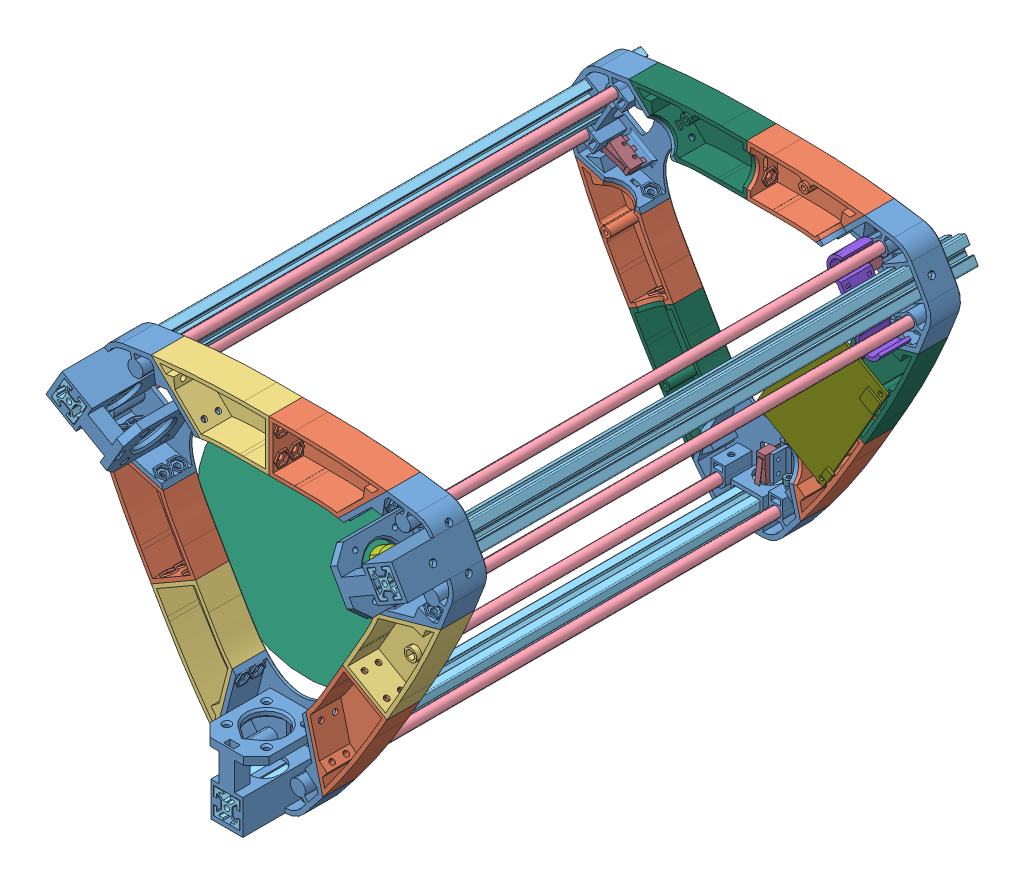
SolidWorks assembly 3DR Simple Delta Printer, configuration Default. Lengths in mm.
Overall size (377.93 326.93 450).
77 component instances, 20 part files, 59 mates.
Components (placement in the parent):
- Bottom Triangle Assembly-1: Bottom Triangle Assembly [Default] at origin size (216 130.25 60.11)
  - 3DR Bottom Motor Mount-1: 3DR Bottom Motor Mount [Simple Center] at origin size (84 76.99 60.11)
  - Wings-1: Wings [Longer with Nut] at (42.1437 10.9951 0) x (0.968477 0.249105 0) z (0 0 1) size (67.81 90.53 27.11)
  - MirrorWings-2: MirrorWings [Default] at (-42.1437 10.9951 0) x (-0.968477 0.249105 0) z (0 0 -1) (suppressed, hidden)
  - MirrorWings1-2: MirrorWings1 [Top With Dimples] at (-42.1437 10.9951 0) x (-0.968477 0.249105 0) z (0 0 -1) (suppressed, hidden)
  - Microswitch-1: Microswitch [Default] at (12 33.25 15) x (0 1 0) z (1 0 0) (suppressed, hidden)
  - Cap Head Screw-1: Cap Head Screw [M4 x 10] at (22.5 12.7724 13.5) x (0.845486 0 0.533998) z (0 1 0) (suppressed, hidden)
  - Wing Mirror Long-1: Wing Mirror Long [Longer With Dimple] at (-134.6068 171.146 0) x (-0.268507 -0.963278 0) z (0 0 1) size (89.72 68.95 27.11)
  - Wing Mirror Long Top-1: Wing Mirror Long Top [Longer Top With Dimples] at (-134.6068 171.146 0) x (-0.268507 -0.963278 0) z (0 0 1) (suppressed, hidden)
- Bottom Triangle Assembly-2: Bottom Triangle Assembly [Default] at (-123.057 213.141 0) x (-0.5 -0.866025 0) z (0 0 1) size (216 130.25 60.11)
  - 3DR Bottom Motor Mount-1: 3DR Bottom Motor Mount [Simple Center] at origin size (84 76.99 60.11)
  - Wings-1: Wings [Longer with Nut] at (42.1437 10.9951 0) x (0.968477 0.249105 0) z (0 0 1) size (67.81 90.53 27.11)
  - MirrorWings-2: MirrorWings [Default] at (-42.1437 10.9951 0) x (-0.968477 0.249105 0) z (0 0 -1) (suppressed, hidden)
  - MirrorWings1-2: MirrorWings1 [Top With Dimples] at (-42.1437 10.9951 0) x (-0.968477 0.249105 0) z (0 0 -1) (suppressed, hidden)
  - Microswitch-1: Microswitch [Default] at (12 33.25 15) x (0 1 0) z (1 0 0) (suppressed, hidden)
  - Cap Head Screw-1: Cap Head Screw [M4 x 10] at (22.5 12.7724 13.5) x (0.845486 0 0.533998) z (0 1 0) (suppressed, hidden)
  - Wing Mirror Long-1: Wing Mirror Long [Longer With Dimple] at (-134.6068 171.146 0) x (-0.268507 -0.963278 0) z (0 0 1) size (89.72 68.95 27.11)
  - Wing Mirror Long Top-1: Wing Mirror Long Top [Longer Top With Dimples] at (-134.6068 171.146 0) x (-0.268507 -0.963278 0) z (0 0 1) (suppressed, hidden)
- Bottom Triangle Assembly-3: Bottom Triangle Assembly [Default] at (123.057 213.141 0) x (-0.5 0.866025 0) z (0 0 1) size (216 130.25 60.11)
  - 3DR Bottom Motor Mount-1: 3DR Bottom Motor Mount [Simple Center] at origin size (84 76.99 60.11)
  - Wings-1: Wings [Longer with Nut] at (42.1437 10.9951 0) x (0.968477 0.249105 0) z (0 0 1) size (67.81 90.53 27.11)
  - MirrorWings-2: MirrorWings [Default] at (-42.1437 10.9951 0) x (-0.968477 0.249105 0) z (0 0 -1) (suppressed, hidden)
  - MirrorWings1-2: MirrorWings1 [Top With Dimples] at (-42.1437 10.9951 0) x (-0.968477 0.249105 0) z (0 0 -1) (suppressed, hidden)
  - Microswitch-1: Microswitch [Default] at (12 33.25 15) x (0 1 0) z (1 0 0) (suppressed, hidden)
  - Cap Head Screw-1: Cap Head Screw [M4 x 10] at (22.5 12.7724 13.5) x (0.845486 0 0.533998) z (0 1 0) (suppressed, hidden)
  - Wing Mirror Long-1: Wing Mirror Long [Longer With Dimple] at (-134.6068 171.146 0) x (-0.268507 -0.963278 0) z (0 0 1) size (89.72 68.95 27.11)
  - Wing Mirror Long Top-1: Wing Mirror Long Top [Longer Top With Dimples] at (-134.6068 171.146 0) x (-0.268507 -0.963278 0) z (0 0 1) (suppressed, hidden)
- RGOCG8-400-1: RGOCG8-400 [Default] at (126.9025 189.3804 -377) size (8 8 400)
- HFSB5-2020-450-1: HFSB5-2020-450 [Default] at (123.2735 213.266 60) x (0.866025 0.5 0) z (0 0 1) size (20 20 450)
- Round Plate-1: Round Plate [Default] at (0 142.094 -5) x (0.976638 0.214891 0) z (0 0 1) size (170 170 3)
- RGOCG8-400-2: RGOCG8-400 [Default] at (104.4025 228.3516 -377) size (8 8 400)
- RGOCG8-400-3: RGOCG8-400 [Default] at (22.5 8.55 -377) size (8 8 400)
- RGOCG8-400-4: RGOCG8-400 [Default] at (-22.5 8.55 -377) size (8 8 400)
- RGOCG8-400-5: RGOCG8-400 [Default] at (-126.9025 189.3804 -377) size (8 8 400)
- RGOCG8-400-6: RGOCG8-400 [Default] at (-104.4025 228.3516 -377) size (8 8 400)
- HFSB5-2020-450-2: HFSB5-2020-450 [Default] at (-123.2735 213.266 60) x (0.5 0.866025 0) z (0 0 1) size (20 20 450)
- HFSB5-2020-450-3: HFSB5-2020-450 [Default] at (0 -0.25 60) size (20 20 450)
- Spiral Bed Clamp-1: Spiral Bed Clamp [Default] at (110.1044 146.1492 -5.917) x (0.34446 -0.938801 0) z (0 0 1) size (25.27 21.2 7.51) (hidden)
- Spool-1: Spool [Default] at (113.3142 207.516 29) x (0.25 -0.433013 0.866025) z (-0.866025 -0.5 0) size (21.5 23.26 25)
- Carriage for LM8UU-1: Carriage for LM8UU [Default] at (113.1669 207.431 -338.0967) x (-0.5 0.866025 0) z (0 0 1) size (65 26.86 24)
- Spectra Idler-1: Spectra Idler [Default] at (109.6336 205.391 -375.1359) x (0 0 1) z (-0.866025 -0.5 0) size (15.69 15.69 24.76)
  - 624ZZ-1: 624ZZ [Default] at origin size (13 13 5)
  - 624ZZ-2: 624ZZ [Default] at (0 0 5) size (13 13 5)
  - Nut-1: Nut [M5] at (0 0 -4.75) size (9.12 7.9 3.75)
  - Washer-1: Washer [M5] at (0 0 10) size (9.75 9.75 1)
  - Washer-2: Washer [M5] at (0 0 -1) size (9.75 9.75 1)
  - Washer-3: Washer [M5 Fender] at (0 0 -5.75) x (0.384822 -0.922991 0) z (0 0 1) size (12 12 1)
  - Button Head Screw-1: Button Head Screw [M5 x 22] at (0 0 -11) size (9.5 9.5 24.76)
- Bottom Triangle Assembly-4: Bottom Triangle Assembly [Top] at (123.057 213.141 -370) x (-0.5 0.866025 0) z (0 0 1) size (216 130.25 28.11)
  - 3DR Bottom Motor Mount-1: 3DR Bottom Motor Mount [Top Microswitch Small] at origin size (84 76.99 24.11)
  - Wings-1: Wings [Longer Top Nuts] at (42.1437 10.9951 0) x (0.968477 0.249105 0) z (0 0 1) size (67.81 90.53 26.11)
  - MirrorWings-2: MirrorWings [Default] at (-42.1437 10.9951 0) x (-0.968477 0.249105 0) z (0 0 -1) (suppressed, hidden)
  - MirrorWings1-2: MirrorWings1 [Top With Dimples] at (-42.1437 10.9951 0) x (-0.968477 0.249105 0) z (0 0 -1) (suppressed, hidden)
  - Microswitch-1: Microswitch [Default] at (12 33.25 15) x (0 1 0) z (1 0 0)
  - Cap Head Screw-1: Cap Head Screw [M4 x 10] at (22.5 12.7724 13.5) x (0.845486 0 0.533998) z (0 1 0)
  - Wing Mirror Long-1: Wing Mirror Long [Longer With Dimple] at (-134.6068 171.146 0) x (-0.268507 -0.963278 0) z (0 0 1) size (89.72 68.95 27.11) (suppressed, hidden)
  - Wing Mirror Long Top-1: Wing Mirror Long Top [Longer Top With Dimples] at (-134.6068 171.146 0) x (-0.268507 -0.963278 0) z (0 0 1)
- Bottom Triangle Assembly-6: Bottom Triangle Assembly [Top] at (-123.057 213.141 -370) x (-0.5 -0.866025 0) z (0 0 1) size (216 130.25 28.11)
  - 3DR Bottom Motor Mount-1: 3DR Bottom Motor Mount [Top Microswitch Small] at origin size (84 76.99 24.11)
  - Wings-1: Wings [Longer Top Nuts] at (42.1437 10.9951 0) x (0.968477 0.249105 0) z (0 0 1) size (67.81 90.53 26.11)
  - MirrorWings-2: MirrorWings [Default] at (-42.1437 10.9951 0) x (-0.968477 0.249105 0) z (0 0 -1) (suppressed, hidden)
  - MirrorWings1-2: MirrorWings1 [Top With Dimples] at (-42.1437 10.9951 0) x (-0.968477 0.249105 0) z (0 0 -1) (suppressed, hidden)
  - Microswitch-1: Microswitch [Default] at (12 33.25 15) x (0 1 0) z (1 0 0)
  - Cap Head Screw-1: Cap Head Screw [M4 x 10] at (22.5 12.7724 13.5) x (0.845486 0 0.533998) z (0 1 0)
  - Wing Mirror Long-1: Wing Mirror Long [Longer With Dimple] at (-134.6068 171.146 0) x (-0.268507 -0.963278 0) z (0 0 1) size (89.72 68.95 27.11) (suppressed, hidden)
  - Wing Mirror Long Top-1: Wing Mirror Long Top [Longer Top With Dimples] at (-134.6068 171.146 0) x (-0.268507 -0.963278 0) z (0 0 1)
- Bottom Triangle Assembly-7: Bottom Triangle Assembly [Top] at (0 0 -370) size (216 130.25 28.11)
  - 3DR Bottom Motor Mount-1: 3DR Bottom Motor Mount [Top Microswitch Small] at origin size (84 76.99 24.11)
  - Wings-1: Wings [Longer Top Nuts] at (42.1437 10.9951 0) x (0.968477 0.249105 0) z (0 0 1) size (67.81 90.53 26.11)
  - MirrorWings-2: MirrorWings [Default] at (-42.1437 10.9951 0) x (-0.968477 0.249105 0) z (0 0 -1) (suppressed, hidden)
  - MirrorWings1-2: MirrorWings1 [Top With Dimples] at (-42.1437 10.9951 0) x (-0.968477 0.249105 0) z (0 0 -1) (suppressed, hidden)
  - Microswitch-1: Microswitch [Default] at (12 33.25 15) x (0 1 0) z (1 0 0)
  - Cap Head Screw-1: Cap Head Screw [M4 x 10] at (22.5 12.7724 13.5) x (0.845486 0 0.533998) z (0 1 0)
  - Wing Mirror Long-1: Wing Mirror Long [Longer With Dimple] at (-134.6068 171.146 0) x (-0.268507 -0.963278 0) z (0 0 1) size (89.72 68.95 27.11) (suppressed, hidden)
  - Wing Mirror Long Top-1: Wing Mirror Long Top [Longer Top With Dimples] at (-134.6068 171.146 0) x (-0.268507 -0.963278 0) z (0 0 1)
- Printrboard-1: Printrboard [Default] at (88.3627 91.0778 -344) x (0.5 0.866025 0) z (0 0 1) size (100.5 62.4 4.3)
- Bed Clip-1: Bed Clip [Default] at (73.6227 115.6588 -6) x (0 0 1) z (0.213458 0.976952 0) size (8 20.01 20)
Mates (geometry in assembly coordinates):
- Coincident1: coincident anti-aligned: plane of Bottom Triangle Assembly-1/MirrorWings-2 through (-47.359 91.6573 3) normal (-0.5 0.866025 0); plane of Bottom Triangle Assembly-2/Wings-1 through (-47.359 91.6573 3) normal (0.5 -0.866025 0)
- Concentric1: concentric anti-aligned: cylinder of Bottom Triangle Assembly-2/Wings-1 through (-109.366 139.0566 9) axis (0.5 -0.866025 0) radius 2.1; cylinder of Bottom Triangle Assembly-1/MirrorWings-2 through (-37.2785 14.1973 9) axis (-0.5 0.866025 0) radius 2.1
- Concentric2: concentric anti-aligned: cylinder of Bottom Triangle Assembly-2/Wings-1 through (-92.0455 149.0566 9) axis (0.5 -0.866025 0) radius 2.1; cylinder of Bottom Triangle Assembly-1/MirrorWings-2 through (-19.958 24.1973 9) axis (-0.5 0.866025 0) radius 2.1
- Coincident2: coincident anti-aligned: plane of Bottom Triangle Assembly-2/MirrorWings-2 through (0 173.6854 3) normal (1 0 0); plane of Bottom Triangle Assembly-3/Wings-1 through (0 173.6854 3) normal (-1 0 0)
- Concentric3: concentric anti-aligned: cylinder of Bottom Triangle Assembly-2/MirrorWings-2 through (-72.1226 203.6854 9) axis (1 0 0) radius 2.1; cylinder of Bottom Triangle Assembly-3/Wings-1 through (72.0526 203.6854 9) axis (-1 0 0) radius 2.1
- Concentric4: concentric anti-aligned: cylinder of Bottom Triangle Assembly-2/MirrorWings-2 through (-72.1226 183.6854 9) axis (1 0 0) radius 2.1; cylinder of Bottom Triangle Assembly-3/Wings-1 through (72.0526 183.6854 9) axis (-1 0 0) radius 2.1
- Width1: width aligned: plane of HFSB5-2020-450-1 through (131.1314 206.2558 -390) normal (0.5 -0.866025 0); plane of HFSB5-2020-450-1 through (126.0678 226.4263 -390) normal (-0.5 0.866025 0); plane of Bottom Triangle Assembly-3/3DR Bottom Motor Mount-1 through (126.8088 227.1428 60) normal (0.5 -0.866025 0); plane of Bottom Triangle Assembly-3/3DR Bottom Motor Mount-1 through (137.0588 209.3893 60) normal (-0.5 0.866025 0)
- Coincident4: coincident anti-aligned: plane of Bottom Triangle Assembly-3/3DR Bottom Motor Mount-1 through (137.0588 209.3893 60) normal (-0.866025 -0.5 0); plane of HFSB5-2020-450-1 through (136.4338 210.4718 -390) normal (0.866025 0.5 0)
- Coincident5: coincident aligned: plane of Bottom Triangle Assembly-3/3DR Bottom Motor Mount-1 through (141.2149 209.1907 60) normal (0 0 1); plane of HFSB5-2020-450-1 through (110.9793 216.5602 60) normal (0 0 1)
- Coincident6: coincident anti-aligned: plane of Bottom Triangle Assembly-3/3DR Bottom Motor Mount-1 through (126.9025 189.3804 23) normal (0 0 -1); circle of RGOCG8-400-1
- Concentric5: concentric aligned: cylinder of Bottom Triangle Assembly-3/3DR Bottom Motor Mount-1 through (126.9025 189.3804 23) axis (0 0 -1) radius 4.15; cylinder of RGOCG8-400-1 through (126.9025 189.3804 23) axis (0 0 -1) radius 4
- Coincident7: coincident: plane of Round Plate-1; line of assembly
- Coincident8: coincident: plane of Round Plate-1
- Concentric6: concentric aligned: cylinder of Bottom Triangle Assembly-3/3DR Bottom Motor Mount-1 through (104.4025 228.3516 23) axis (0 0 -1) radius 4.15; cylinder of RGOCG8-400-2 through (104.4025 228.3516 23) axis (0 0 -1) radius 4
- Coincident10: coincident aligned: plane of RGOCG8-400-1 through (126.9025 189.3804 -377) normal (0 0 1); plane of RGOCG8-400-2 through (104.4025 228.3516 -377) normal (0 0 1)
- Concentric7: concentric aligned: circle of Bottom Triangle Assembly-1/3DR Bottom Motor Mount-1; cylinder of RGOCG8-400-3 through (22.5 8.55 23) axis (0 0 -1) radius 4
- Concentric8: concentric aligned: cylinder of Bottom Triangle Assembly-1/3DR Bottom Motor Mount-1 through (-22.5 8.55 23) axis (0 0 -1) radius 4.15; cylinder of RGOCG8-400-4 through (-22.5 8.55 23) axis (0 0 -1) radius 4
- Coincident18: coincident aligned: plane of RGOCG8-400-2 through (104.4025 228.3516 -377) normal (0 0 1); plane of RGOCG8-400-3 through (22.5 8.55 -377) normal (0 0 1)
- Coincident19: coincident aligned: plane of RGOCG8-400-2 through (104.4025 228.3516 -377) normal (0 0 1); plane of RGOCG8-400-4 through (-22.5 8.55 -377) normal (0 0 1)
- Concentric9: concentric aligned: cylinder of Bottom Triangle Assembly-2/3DR Bottom Motor Mount-1 through (-126.9025 189.3804 23) axis (0 0 -1) radius 4.15; cylinder of RGOCG8-400-5 through (-126.9025 189.3804 23) axis (0 0 -1) radius 4
- Coincident22: coincident aligned: plane of RGOCG8-400-1 through (126.9025 189.3804 -377) normal (0 0 1); plane of RGOCG8-400-5 through (-126.9025 189.3804 -377) normal (0 0 1)
- Concentric10: concentric aligned: cylinder of Bottom Triangle Assembly-2/3DR Bottom Motor Mount-1 through (-104.4025 228.3516 23) axis (0 0 -1) radius 4.15; cylinder of RGOCG8-400-6 through (-104.4025 228.3516 23) axis (0 0 -1) radius 4
- Coincident23: coincident aligned: plane of RGOCG8-400-1 through (126.9025 189.3804 -377) normal (0 0 1); plane of RGOCG8-400-6 through (-104.4025 228.3516 -377) normal (0 0 1)
- Coincident24: coincident anti-aligned: plane of Bottom Triangle Assembly-2/3DR Bottom Motor Mount-1 through (-126.8088 227.1428 60) normal (0.866025 -0.5 0); plane of HFSB5-2020-450-2 through (-127.4338 226.0602 -390) normal (-0.866025 0.5 0)
- Width2: width anti-aligned: plane of Bottom Triangle Assembly-2/3DR Bottom Motor Mount-1 through (-137.0588 209.3893 60) normal (0.5 0.866025 0); plane of Bottom Triangle Assembly-2/3DR Bottom Motor Mount-1 through (-126.8088 227.1428 60) normal (-0.5 -0.866025 0); plane of HFSB5-2020-450-2 through (-136.0678 209.1058 -390) normal (-0.5 -0.866025 0); plane of HFSB5-2020-450-2 through (-121.1314 223.5763 -390) normal (0.5 0.866025 0)
- Coincident25: coincident aligned: plane of HFSB5-2020-450-1 through (123.2735 213.266 60) normal (0 0 1); plane of HFSB5-2020-450-2 through (-123.2735 213.266 60) normal (0 0 1)
- Coincident26: coincident anti-aligned: plane of Bottom Triangle Assembly-1/3DR Bottom Motor Mount-1 through (-10.25 -10.25 60) normal (0 1 0); plane of HFSB5-2020-450-3 through (-9 -10.25 -390) normal (0 -1 0)
- Width3: width anti-aligned: plane of Bottom Triangle Assembly-1/3DR Bottom Motor Mount-1 through (10.25 -10.25 60) normal (-1 0 0); plane of Bottom Triangle Assembly-1/3DR Bottom Motor Mount-1 through (-10.25 -10.25 60) normal (1 0 0); plane of HFSB5-2020-450-3 through (10 3.05 -390) normal (1 0 0); plane of HFSB5-2020-450-3 through (-10 8.75 -390) normal (-1 0 0)
- Coincident27: coincident aligned: plane of HFSB5-2020-450-1 through (123.2735 213.266 60) normal (0 0 1); plane of HFSB5-2020-450-3 through (0 -0.25 60) normal (0 0 1)
- Coincident28: coincident anti-aligned: plane of Bottom Triangle Assembly-3/MirrorWings-2 through (-409.8106 355.6043 0) normal (0 0 -1); plane of Spiral Bed Clamp-1 through (93.9348 115.4982 0) normal (0 0 1)
- Concentric11: concentric anti-aligned: cylinder of ? through (93.9348 115.4982 27) axis (0 0 -1) radius 1.65; cylinder of ? through (93.9348 115.4982 -3.5) axis (0 0 1) radius 1.75
- Concentric12: concentric anti-aligned: cylinder of Spool-1 through (100.3239 200.016 29) axis (0.866025 0.5 0) radius 9; cylinder of Bottom Triangle Assembly-3/3DR Bottom Motor Mount-1 through (133.2434 219.0221 29) axis (-0.866025 -0.5 0) radius 14.5
- Distance1: distance = 5 mm aligned: plane of Spool-1 through (91.6636 195.016 29) normal (-0.866025 -0.5 0); plane of Bottom Triangle Assembly-3/3DR Bottom Motor Mount-1 through (98.8335 172.5974 0) normal (-0.866025 -0.5 0)
- Concentric20: concentric aligned: cylinder of RGOCG8-400-1 through (126.9025 189.3804 23) axis (0 0 -1) radius 4; cylinder of Carriage for LM8UU-1 through (126.9025 189.3804 -314.0967) axis (0 0 -1) radius 7.5
- Concentric21: concentric aligned: cylinder of RGOCG8-400-2 through (104.4025 228.3516 23) axis (0 0 -1) radius 4; cylinder of Carriage for LM8UU-1 through (104.4025 228.3516 -314.0967) axis (0 0 -1) radius 7.5
- Coincident30: coincident anti-aligned: plane of HFSB5-2020-450-1 through (110.1133 216.0602 -390) normal (-0.866025 -0.5 0); plane of Spectra Idler-1/Washer-3 through (114.6133 208.266 -375.1359) normal (0.866025 0.5 0)
- Concentric22: concentric aligned: cylinder of RGOCG8-400-1 through (126.9025 189.3804 23) axis (0 0 -1) radius 4; cylinder of Bottom Triangle Assembly-4/3DR Bottom Motor Mount-1 through (126.9025 189.3804 -347) axis (0 0 -1) radius 4.25
- Concentric23: concentric aligned: cylinder of RGOCG8-400-2 through (104.4025 228.3516 23) axis (0 0 -1) radius 4; cylinder of Bottom Triangle Assembly-4/3DR Bottom Motor Mount-1 through (104.4025 228.3516 -347) axis (0 0 -1) radius 4.25
- Distance2: distance = 20 mm aligned: plane of Bottom Triangle Assembly-4/3DR Bottom Motor Mount-1 through (141.2149 209.1907 -370) normal (0 0 -1); plane of HFSB5-2020-450-1 through (110.9793 216.5602 -390) normal (0 0 -1)
- Coincident32: coincident aligned: plane of Bottom Triangle Assembly-4/3DR Bottom Motor Mount-1 through (141.2149 209.1907 -370) normal (0 0 -1); plane of Bottom Triangle Assembly-7/3DR Bottom Motor Mount-1 through (-12.5 -13.75 -370) normal (0 0 -1)
- Coincident33: coincident aligned: plane of Bottom Triangle Assembly-4/3DR Bottom Motor Mount-1 through (141.2149 209.1907 -370) normal (0 0 -1); plane of Bottom Triangle Assembly-6/3DR Bottom Motor Mount-1 through (-128.7149 230.8413 -370) normal (0 0 -1)
- Concentric24: concentric aligned: cylinder of RGOCG8-400-3 through (22.5 8.55 23) axis (0 0 -1) radius 4; cylinder of Bottom Triangle Assembly-7/3DR Bottom Motor Mount-1 through (22.5 8.55 -347) axis (0 0 -1) radius 4.25
- Concentric26: concentric aligned: cylinder of RGOCG8-400-4 through (-22.5 8.55 23) axis (0 0 -1) radius 4; cylinder of Bottom Triangle Assembly-7/3DR Bottom Motor Mount-1 through (-22.5 8.55 -347) axis (0 0 -1) radius 4.25
- Concentric27: concentric aligned: cylinder of RGOCG8-400-5 through (-126.9025 189.3804 23) axis (0 0 -1) radius 4; cylinder of Bottom Triangle Assembly-6/3DR Bottom Motor Mount-1 through (-126.9025 189.3804 -347) axis (0 0 -1) radius 4.25
- Concentric28: concentric aligned: cylinder of RGOCG8-400-6 through (-104.4025 228.3516 23) axis (0 0 -1) radius 4; cylinder of Bottom Triangle Assembly-6/3DR Bottom Motor Mount-1 through (-104.4025 228.3516 -347) axis (0 0 -1) radius 4.25
- Coincident34: coincident anti-aligned: plane of Bottom Triangle Assembly-4/MirrorWings1-2 through (128.7149 230.8413 -344) normal (0 0 1); plane of Printrboard-1 through (73.8933 64.5389 -344) normal (0 0 -1)
- Concentric29: concentric anti-aligned: cylinder of ? through (51.9468 35.6036 -503.2478) axis (0 0 -1) radius 3.8; cylinder of ? through (51.9468 35.6036 -515.9969) axis (0 0 1) radius 1.75
- Concentric30: concentric anti-aligned: cylinder of ? through (118.1968 150.352 -331.252) axis (0 0 -1) radius 3.8; cylinder of ? through (118.1968 150.352 -344.001) axis (0 0 1) radius 1.75
- Coincident36: coincident anti-aligned: plane of Bottom Triangle Assembly-1/Wings-1 through (57.359 108.9778 62.9973) normal (0.5 0.866025 0); plane of Bottom Triangle Assembly-3/Wing Mirror Long-1 through (57.359 108.9778 62.9973) normal (-0.5 -0.866025 0)
- Concentric31: concentric anti-aligned: cylinder of ? through (19.958 24.1973 9) axis (0.5 0.866025 0) radius 2.1; cylinder of ? through (112.0805 183.7583 9) axis (-0.5 -0.866025 0) radius 2.1
- Coincident37: coincident anti-aligned: plane of ? through (-57.359 108.9778 62.9973) normal (-0.5 0.866025 0); plane of Bottom Triangle Assembly-2/Wings-1 through (-57.359 108.9778 62.9973) normal (0.5 -0.866025 0)
- Concentric32: concentric anti-aligned: cylinder of ? through (-19.958 24.1973 20) axis (-0.5 0.866025 0) radius 2.1; cylinder of Bottom Triangle Assembly-2/Wings-1 through (-112.0805 183.7583 20) axis (0.5 -0.866025 0) radius 2.1
- Width4: width anti-aligned: plane of Spectra Idler-1/Nut-1 through (112.4747 202.4702 -377.4165) normal (0.5 -0.866025 0); plane of Spectra Idler-1/Nut-1 through (108.5247 209.3118 -372.8554) normal (-0.5 0.866025 0); plane of HFSB5-2020-450-1 through (117.8453 206.6679 -390) normal (-0.5 0.866025 0); plane of HFSB5-2020-450-1 through (113.3731 211.0141 -390) normal (0.5 -0.866025 0)
- Coincident38: coincident anti-aligned: plane of ? through (-389.8106 390.2453 0) normal (0 0 -1); plane of Bed Clip-1 through (85.7075 133.4902 0) normal (0 0 1)
- Concentric33: concentric aligned: cylinder of ? through (90.4115 122.2265 -0.1091) axis (0 0 1) radius 1.65; cylinder of Bed Clip-1 through (90.4115 122.2265 -8) axis (0 0 1) radius 1.75
- Coincident39: coincident anti-aligned: plane of Round Plate-1 through (0 142.094 -2) normal (0 0 1); plane of Bed Clip-1 through (85.7075 133.4902 -2) normal (0 0 -1)
- Concentric34: concentric aligned: circle of ?; cylinder of Printrboard-1 through (61.9468 52.9241 -344.001) axis (0 0 1) radius 1.75
- Concentric35: concentric anti-aligned: circle of ?; cylinder of Printrboard-1 through (108.1968 133.0315 -344.001) axis (0 0 1) radius 1.75
- Coincident40: coincident anti-aligned: plane of ? through (-389.8106 390.2453 -344) normal (0 0 1); plane of Printrboard-1 through (63.2377 47.56 -344) normal (0 0 -1)
